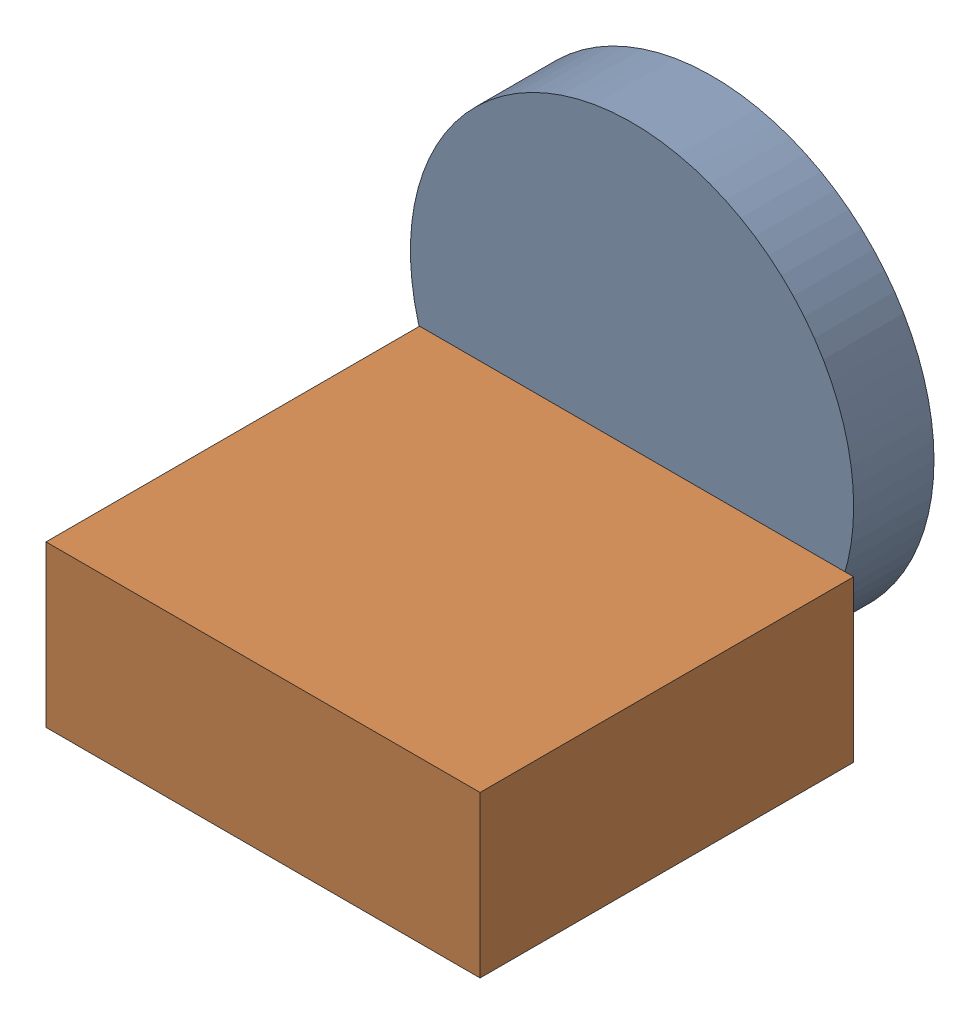
SolidWorks assembly Assem1_ms, configuration Default. Lengths in mm.
Overall size (55.17 55.17 62.23).
3 component instances, 3 part files, 5 mates.
Components (placement in the parent):
- Part1-1: Part1 [Default] at (-24.8178 11.3429 7.7042) size (55.17 55.17 10)
- Part2-1: Part2 [Default] at (-25.2044 -13.3142 44.4214) x (1 0 0) z (0 1 0) size (54.03 46.5 20)
- ISO 7380-1 M3x4mm v7-1: ISO 7380-1 M3x4mm v7 [Default] at (-31.2132 14.2716 6.0542) size (5.7 5.7 5.73)
Mates (geometry in assembly coordinates):
- Concentric1: concentric anti-aligned: circle of Part1-1; circle of ISO 7380-1 M3x4mm v7-1
- Coincident1: coincident anti-aligned: plane of Part1-1 through (-31.2132 14.2716 7.7042) normal (0 0 -1); plane of ISO 7380-1 M3x4mm v7-1 through (-31.2132 16.0962 7.7042) normal (0 0 1)
- Coincident2: coincident anti-aligned: plane of Part1-1 through (-31.2132 14.2716 17.7042) normal (0 0 1); plane of Part2-1 through (-57.6595 6.6858 17.7042) normal (0 0 -1)
- Tangent1: tangent aligned: cylinder of Part1-1 through (-31.2132 14.2716 17.7042) axis (0 0 -1) radius 27.5858; plane of Part2-1 through (-25.2044 -13.3142 44.4214) normal (0 -1 0)
- Tangent2: tangent aligned: cylinder of Part1-1 through (-31.2132 14.2716 17.7042) axis (0 0 -1) radius 27.5858; plane of Part2-1 through (-3.6275 6.6858 64.2053) normal (1 0 0)
